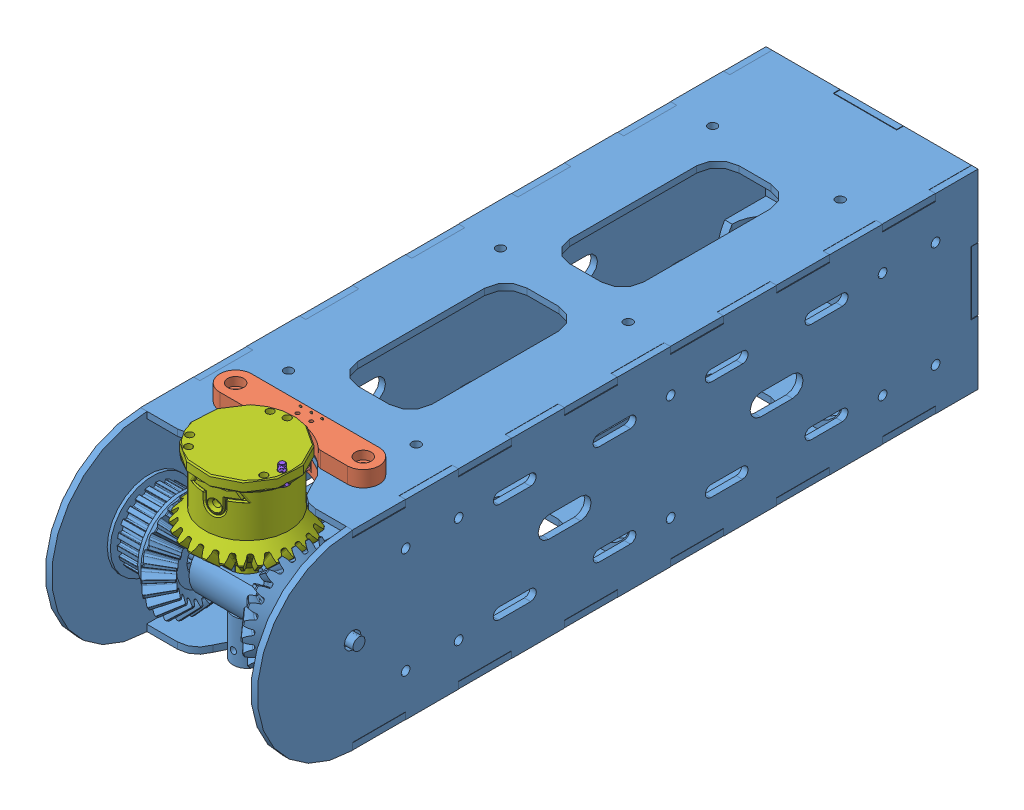
SolidWorks assembly Limit Switch Mount, configuration Default. Lengths in mm.
Overall size (106 103.9 340).
15 component instances, 8 part files, 15 mates.
Components (placement in the parent):
- Robot-Arm-P1-Stepper v21-1: Robot-Arm-P1-Stepper v21 [Default] at (46.1 0 0) x (0 0 1) z (0 -1 0) size (340 106 90)
- Limit Switch Mount-1: Limit Switch Mount [Bolt] at origin size (75.2 7.5 15)
- Micro limit switch-1: Micro limit switch [Default] at (0 45.1 -27.15) x (0 1 0) z (1 0 0) size (8.15 12.86 13.95)
  - PINS___ _________-1: PINS___ _________ [Default] at origin size (8.05 4.8 12.8)
  - High_Part___ _________-1: High_Part___ _________ [Default] at origin size (5.8 6 12.8)
  - Button___ _________-1: Button___ _________ [Default] at origin size (3.6 1.19 1.2)
  - Plate-1: Plate [Default] at (4.35 6.2428 -1.95) x (0 0 1) z (-1 0 0) size (13.35 5.26 3)
- Limit Switch Mount-2: Limit Switch Mount [Nut] at (-0.2 87 0) x (-1 0 0) z (0 0 1) size (75.2 7.5 15)
- Micro limit switch-2: Micro limit switch [Default] at (-0.2 41.9 -25.15) x (0 -1 0) z (-1 0 0) size (8.15 12.86 13.95)
  - PINS___ _________-1: PINS___ _________ [Default] at origin size (8.05 4.8 12.8)
  - High_Part___ _________-1: High_Part___ _________ [Default] at origin size (5.8 6 12.8)
  - Button___ _________-1: Button___ _________ [Default] at origin size (3.6 1.19 1.2)
  - Plate-1: Plate [Default] at (4.35 6.2428 -1.95) x (0 0 1) z (-1 0 0) size (13.35 5.26 3)
- Output Gear-1: Output Gear [Default] at (-44.9428 -0.2 9.3647) x (-0.203566 0 -0.979061) z (0 -1 0) size (52.23 52.33 87.9)
- M3x8mm Flat Head Bolt-1: M3x8mm Flat Head Bolt [92125A128] at (19.5137 54.715 2.8168) x (1 0 0) z (0 -1 0) size (6 6 8.29)
Mates (geometry in assembly coordinates):
- Symmetric1: symmetric aligned: plane of Robot-Arm-P1-Stepper v21-1 through (-50 0 -125) normal (-1 0 0); plane of Robot-Arm-P1-Stepper v21-1 through (50 0 -125) normal (1 0 0)
- Symmetric2: symmetric aligned: plane of Robot-Arm-P1-Stepper v21-1 through (-0.1 -45 -160) normal (0 -1 0); plane of Robot-Arm-P1-Stepper v21-1 through (-0.1 45 -160) normal (0 1 0)
- Coincident1: coincident aligned: plane of Robot-Arm-P1-Stepper v21-1 through (46.1 0 0) normal (0 0 1)
- Concentric1: concentric anti-aligned: cylinder of Part5^Limit Switch Mount-1 through (-3.25 52.5 -27.2) axis (0 -1 0) radius 0.85; cylinder of Micro limit switch-1/PINS___ _________-1 through (-3.25 41.9887 -27.2) axis (0 1 0) radius 1.1
- Concentric2: concentric anti-aligned: cylinder of Part5^Limit Switch Mount-1 through (3.25 52.5 -27.2) axis (0 -1 0) radius 0.85; cylinder of Micro limit switch-1/PINS___ _________-1 through (3.25 41.9887 -27.2) axis (0 1 0) radius 1.1
- Coincident2: coincident anti-aligned: plane of Limit Switch Mount-1 through (0 50.8 0) normal (0 -1 0); plane of Micro limit switch-1/High_Part___ _________-1 through (0 50.8 -27.15) normal (0 1 0)
- Concentric3: concentric anti-aligned: cylinder of Part5^Limit Switch Mount-1 through (30 52.5 -25) axis (0 -1 0) radius 7.5; cylinder of Part5^Limit Switch Mount-2 through (30 34.5 -25) axis (0 1 0) radius 7.5
- Concentric4: concentric anti-aligned: cylinder of Part5^Limit Switch Mount-1 through (-30.2 52.5 -25) axis (0 -1 0) radius 7.5; cylinder of Part5^Limit Switch Mount-2 through (-30.2 34.5 -25) axis (0 1 0) radius 7.5
- Coincident3: coincident anti-aligned: plane of Robot-Arm-P1-Stepper v21-1 through (-0.1 42 -160) normal (0 -1 0); plane of Part5^Limit Switch Mount-2 through (-0.1 42 0) normal (0 1 0)
- Concentric5: concentric anti-aligned: cylinder of Part5^Limit Switch Mount-2 through (-3.45 34.5 -25.2) axis (0 1 0) radius 0.85; cylinder of Micro limit switch-2/PINS___ _________-1 through (-3.45 45.0113 -25.2) axis (0 -1 0) radius 1.1
- Concentric6: concentric anti-aligned: cylinder of Part5^Limit Switch Mount-2 through (3.05 34.5 -25.2) axis (0 1 0) radius 0.85; cylinder of Micro limit switch-2/PINS___ _________-1 through (3.05 45.0113 -25.2) axis (0 -1 0) radius 1.1
- Coincident4: coincident anti-aligned: plane of Part5^Limit Switch Mount-2 through (-0.1 36.2 0) normal (0 1 0); plane of Micro limit switch-2/High_Part___ _________-1 through (-0.2 36.2 -25.15) normal (0 -1 0)
- Concentric7: concentric anti-aligned: cylinder of Robot-Arm-P1-Stepper v21-1 through (0.097 -9 0) axis (0 1 0) radius 5.5; cylinder of Output Gear-1 through (0.097 7.8 0) axis (0 -1 0) radius 3.9
- Coincident5: coincident anti-aligned: plane of Robot-Arm-P1-Stepper v21-1 through (0.1 7.9 0) normal (0 1 0); plane of Output Gear-1 through (0.097 7.9 0) normal (0 -1 0)
- Coincident6: coincident aligned: cone of Output Gear-1 through (19.5137 50.8 2.8168) axis (0 1 0); cone of M3x8mm Flat Head Bolt-1 through (19.5137 50.8 2.8168) axis (0 1 0)
